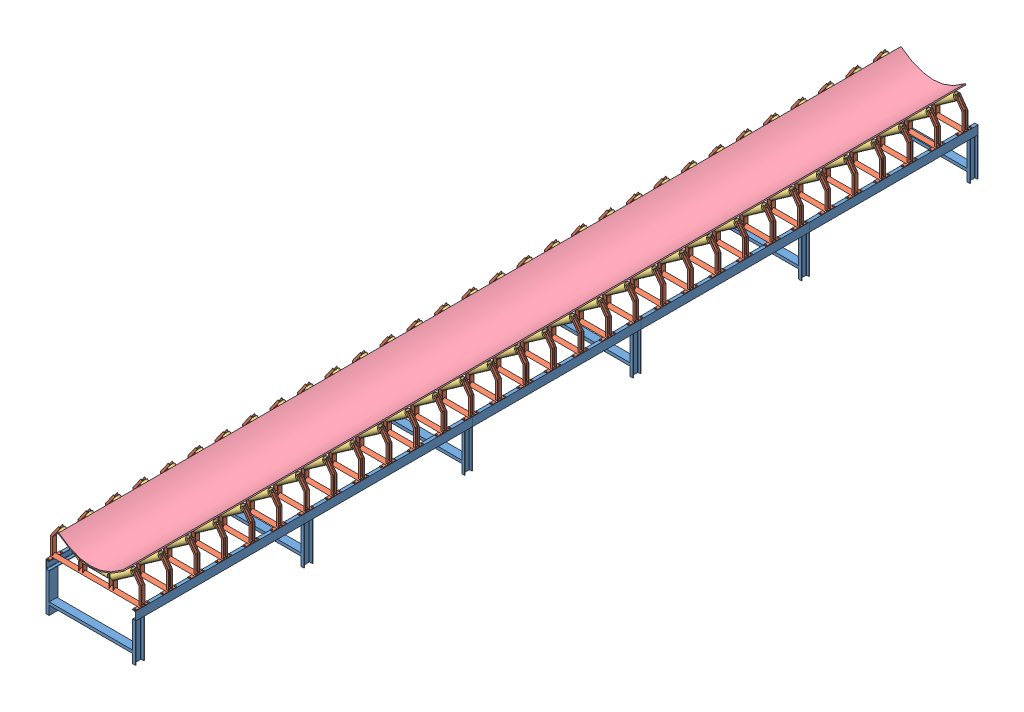
SolidWorks assembly Transportador, configuration Valor predeterminado. Lengths in mm.
Overall size (2310 1983.02 21500).
157 component instances, 4 part files, 8 mates.
Components (placement in the parent):
- Estrutura-1: Estrutura [Valor predeterminado<Como usinado>] at (49.1652 530.0341 0) size (2290 1200 21500)
- Desck3rolos-1: Desck3rolos [Valor predeterminado] at (242.5797 979.3864 -2491.6) size (2310 783.02 360)
  - Cavalete1800-1: Cavalete1800 [Valor predeterminado<Como usinado>] at (-193.4145 -362.4269 2311.6) size (2310 755.58 360)
  - RolodeCarga-1: RolodeCarga [Valor predeterminado] at (-860.2898 54.9269 2311.6) x (0.819152 -0.573576 0) z (-0.563806 -0.805199 0.183788) size (697 165 165)
  - RolodeCarga-2: RolodeCarga [Valor predeterminado] at (-193.4145 -134.9269 2311.6) x (-1 0 0) z (0 0.924225 0.381849) size (697 165 165)
  - RolodeCarga-3: RolodeCarga [Valor predeterminado] at (473.4609 54.9269 2311.6) x (0.819152 0.573576 0) z (0 0 1) size (697 165 165)
- Desck3rolos-2: Desck3rolos [Valor predeterminado] at (242.5797 979.3864 -3191.6) size (2310 783.02 360)
  - Cavalete1800-1: Cavalete1800 [Valor predeterminado<Como usinado>] at (-193.4145 -362.4269 2311.6) size (2310 755.58 360)
  - RolodeCarga-1: RolodeCarga [Valor predeterminado] at (-860.2898 54.9269 2311.6) x (0.819152 -0.573576 0) z (-0.563806 -0.805199 0.183788) size (697 165 165)
  - RolodeCarga-2: RolodeCarga [Valor predeterminado] at (-193.4145 -134.9269 2311.6) x (-1 0 0) z (0 0.924225 0.381849) size (697 165 165)
  - RolodeCarga-3: RolodeCarga [Valor predeterminado] at (473.4609 54.9269 2311.6) x (0.819152 0.573576 0) z (0 0 1) size (697 165 165)
- Desck3rolos-3: Desck3rolos [Valor predeterminado] at (242.5797 979.3864 -3891.6) size (2310 783.02 360)
  - Cavalete1800-1: Cavalete1800 [Valor predeterminado<Como usinado>] at (-193.4145 -362.4269 2311.6) size (2310 755.58 360)
  - RolodeCarga-1: RolodeCarga [Valor predeterminado] at (-860.2898 54.9269 2311.6) x (0.819152 -0.573576 0) z (-0.563806 -0.805199 0.183788) size (697 165 165)
  - RolodeCarga-2: RolodeCarga [Valor predeterminado] at (-193.4145 -134.9269 2311.6) x (-1 0 0) z (0 0.924225 0.381849) size (697 165 165)
  - RolodeCarga-3: RolodeCarga [Valor predeterminado] at (473.4609 54.9269 2311.6) x (0.819152 0.573576 0) z (0 0 1) size (697 165 165)
- Desck3rolos-4: Desck3rolos [Valor predeterminado] at (242.5797 979.3864 -4591.6) size (2310 783.02 360)
  - Cavalete1800-1: Cavalete1800 [Valor predeterminado<Como usinado>] at (-193.4145 -362.4269 2311.6) size (2310 755.58 360)
  - RolodeCarga-1: RolodeCarga [Valor predeterminado] at (-860.2898 54.9269 2311.6) x (0.819152 -0.573576 0) z (-0.563806 -0.805199 0.183788) size (697 165 165)
  - RolodeCarga-2: RolodeCarga [Valor predeterminado] at (-193.4145 -134.9269 2311.6) x (-1 0 0) z (0 0.924225 0.381849) size (697 165 165)
  - RolodeCarga-3: RolodeCarga [Valor predeterminado] at (473.4609 54.9269 2311.6) x (0.819152 0.573576 0) z (0 0 1) size (697 165 165)
- Desck3rolos-5: Desck3rolos [Valor predeterminado] at (242.5797 979.3864 -5291.6) size (2310 783.02 360)
  - Cavalete1800-1: Cavalete1800 [Valor predeterminado<Como usinado>] at (-193.4145 -362.4269 2311.6) size (2310 755.58 360)
  - RolodeCarga-1: RolodeCarga [Valor predeterminado] at (-860.2898 54.9269 2311.6) x (0.819152 -0.573576 0) z (-0.563806 -0.805199 0.183788) size (697 165 165)
  - RolodeCarga-2: RolodeCarga [Valor predeterminado] at (-193.4145 -134.9269 2311.6) x (-1 0 0) z (0 0.924225 0.381849) size (697 165 165)
  - RolodeCarga-3: RolodeCarga [Valor predeterminado] at (473.4609 54.9269 2311.6) x (0.819152 0.573576 0) z (0 0 1) size (697 165 165)
- Desck3rolos-6: Desck3rolos [Valor predeterminado] at (242.5797 979.3864 -5991.6) size (2310 783.02 360)
  - Cavalete1800-1: Cavalete1800 [Valor predeterminado<Como usinado>] at (-193.4145 -362.4269 2311.6) size (2310 755.58 360)
  - RolodeCarga-1: RolodeCarga [Valor predeterminado] at (-860.2898 54.9269 2311.6) x (0.819152 -0.573576 0) z (-0.563806 -0.805199 0.183788) size (697 165 165)
  - RolodeCarga-2: RolodeCarga [Valor predeterminado] at (-193.4145 -134.9269 2311.6) x (-1 0 0) z (0 0.924225 0.381849) size (697 165 165)
  - RolodeCarga-3: RolodeCarga [Valor predeterminado] at (473.4609 54.9269 2311.6) x (0.819152 0.573576 0) z (0 0 1) size (697 165 165)
- Desck3rolos-7: Desck3rolos [Valor predeterminado] at (242.5797 979.3864 -6691.6) size (2310 783.02 360)
  - Cavalete1800-1: Cavalete1800 [Valor predeterminado<Como usinado>] at (-193.4145 -362.4269 2311.6) size (2310 755.58 360)
  - RolodeCarga-1: RolodeCarga [Valor predeterminado] at (-860.2898 54.9269 2311.6) x (0.819152 -0.573576 0) z (-0.563806 -0.805199 0.183788) size (697 165 165)
  - RolodeCarga-2: RolodeCarga [Valor predeterminado] at (-193.4145 -134.9269 2311.6) x (-1 0 0) z (0 0.924225 0.381849) size (697 165 165)
  - RolodeCarga-3: RolodeCarga [Valor predeterminado] at (473.4609 54.9269 2311.6) x (0.819152 0.573576 0) z (0 0 1) size (697 165 165)
- Desck3rolos-8: Desck3rolos [Valor predeterminado] at (242.5797 979.3864 -7391.6) size (2310 783.02 360)
  - Cavalete1800-1: Cavalete1800 [Valor predeterminado<Como usinado>] at (-193.4145 -362.4269 2311.6) size (2310 755.58 360)
  - RolodeCarga-1: RolodeCarga [Valor predeterminado] at (-860.2898 54.9269 2311.6) x (0.819152 -0.573576 0) z (-0.563806 -0.805199 0.183788) size (697 165 165)
  - RolodeCarga-2: RolodeCarga [Valor predeterminado] at (-193.4145 -134.9269 2311.6) x (-1 0 0) z (0 0.924225 0.381849) size (697 165 165)
  - RolodeCarga-3: RolodeCarga [Valor predeterminado] at (473.4609 54.9269 2311.6) x (0.819152 0.573576 0) z (0 0 1) size (697 165 165)
- Desck3rolos-9: Desck3rolos [Valor predeterminado] at (242.5797 979.3864 -8091.6) size (2310 783.02 360)
  - Cavalete1800-1: Cavalete1800 [Valor predeterminado<Como usinado>] at (-193.4145 -362.4269 2311.6) size (2310 755.58 360)
  - RolodeCarga-1: RolodeCarga [Valor predeterminado] at (-860.2898 54.9269 2311.6) x (0.819152 -0.573576 0) z (-0.563806 -0.805199 0.183788) size (697 165 165)
  - RolodeCarga-2: RolodeCarga [Valor predeterminado] at (-193.4145 -134.9269 2311.6) x (-1 0 0) z (0 0.924225 0.381849) size (697 165 165)
  - RolodeCarga-3: RolodeCarga [Valor predeterminado] at (473.4609 54.9269 2311.6) x (0.819152 0.573576 0) z (0 0 1) size (697 165 165)
- Desck3rolos-10: Desck3rolos [Valor predeterminado] at (242.5797 979.3864 -8791.6) size (2310 783.02 360)
  - Cavalete1800-1: Cavalete1800 [Valor predeterminado<Como usinado>] at (-193.4145 -362.4269 2311.6) size (2310 755.58 360)
  - RolodeCarga-1: RolodeCarga [Valor predeterminado] at (-860.2898 54.9269 2311.6) x (0.819152 -0.573576 0) z (-0.563806 -0.805199 0.183788) size (697 165 165)
  - RolodeCarga-2: RolodeCarga [Valor predeterminado] at (-193.4145 -134.9269 2311.6) x (-1 0 0) z (0 0.924225 0.381849) size (697 165 165)
  - RolodeCarga-3: RolodeCarga [Valor predeterminado] at (473.4609 54.9269 2311.6) x (0.819152 0.573576 0) z (0 0 1) size (697 165 165)
- Desck3rolos-11: Desck3rolos [Valor predeterminado] at (242.5797 979.3864 -9491.6) size (2310 783.02 360)
  - Cavalete1800-1: Cavalete1800 [Valor predeterminado<Como usinado>] at (-193.4145 -362.4269 2311.6) size (2310 755.58 360)
  - RolodeCarga-1: RolodeCarga [Valor predeterminado] at (-860.2898 54.9269 2311.6) x (0.819152 -0.573576 0) z (-0.563806 -0.805199 0.183788) size (697 165 165)
  - RolodeCarga-2: RolodeCarga [Valor predeterminado] at (-193.4145 -134.9269 2311.6) x (-1 0 0) z (0 0.924225 0.381849) size (697 165 165)
  - RolodeCarga-3: RolodeCarga [Valor predeterminado] at (473.4609 54.9269 2311.6) x (0.819152 0.573576 0) z (0 0 1) size (697 165 165)
- Desck3rolos-12: Desck3rolos [Valor predeterminado] at (242.5797 979.3864 -10191.6) size (2310 783.02 360)
  - Cavalete1800-1: Cavalete1800 [Valor predeterminado<Como usinado>] at (-193.4145 -362.4269 2311.6) size (2310 755.58 360)
  - RolodeCarga-1: RolodeCarga [Valor predeterminado] at (-860.2898 54.9269 2311.6) x (0.819152 -0.573576 0) z (-0.563806 -0.805199 0.183788) size (697 165 165)
  - RolodeCarga-2: RolodeCarga [Valor predeterminado] at (-193.4145 -134.9269 2311.6) x (-1 0 0) z (0 0.924225 0.381849) size (697 165 165)
  - RolodeCarga-3: RolodeCarga [Valor predeterminado] at (473.4609 54.9269 2311.6) x (0.819152 0.573576 0) z (0 0 1) size (697 165 165)
- Desck3rolos-13: Desck3rolos [Valor predeterminado] at (242.5797 979.3864 -10891.6) size (2310 783.02 360)
  - Cavalete1800-1: Cavalete1800 [Valor predeterminado<Como usinado>] at (-193.4145 -362.4269 2311.6) size (2310 755.58 360)
  - RolodeCarga-1: RolodeCarga [Valor predeterminado] at (-860.2898 54.9269 2311.6) x (0.819152 -0.573576 0) z (-0.563806 -0.805199 0.183788) size (697 165 165)
  - RolodeCarga-2: RolodeCarga [Valor predeterminado] at (-193.4145 -134.9269 2311.6) x (-1 0 0) z (0 0.924225 0.381849) size (697 165 165)
  - RolodeCarga-3: RolodeCarga [Valor predeterminado] at (473.4609 54.9269 2311.6) x (0.819152 0.573576 0) z (0 0 1) size (697 165 165)
- Desck3rolos-14: Desck3rolos [Valor predeterminado] at (242.5797 979.3864 -11591.6) size (2310 783.02 360)
  - Cavalete1800-1: Cavalete1800 [Valor predeterminado<Como usinado>] at (-193.4145 -362.4269 2311.6) size (2310 755.58 360)
  - RolodeCarga-1: RolodeCarga [Valor predeterminado] at (-860.2898 54.9269 2311.6) x (0.819152 -0.573576 0) z (-0.563806 -0.805199 0.183788) size (697 165 165)
  - RolodeCarga-2: RolodeCarga [Valor predeterminado] at (-193.4145 -134.9269 2311.6) x (-1 0 0) z (0 0.924225 0.381849) size (697 165 165)
  - RolodeCarga-3: RolodeCarga [Valor predeterminado] at (473.4609 54.9269 2311.6) x (0.819152 0.573576 0) z (0 0 1) size (697 165 165)
- Desck3rolos-15: Desck3rolos [Valor predeterminado] at (242.5797 979.3864 -12291.6) size (2310 783.02 360)
  - Cavalete1800-1: Cavalete1800 [Valor predeterminado<Como usinado>] at (-193.4145 -362.4269 2311.6) size (2310 755.58 360)
  - RolodeCarga-1: RolodeCarga [Valor predeterminado] at (-860.2898 54.9269 2311.6) x (0.819152 -0.573576 0) z (-0.563806 -0.805199 0.183788) size (697 165 165)
  - RolodeCarga-2: RolodeCarga [Valor predeterminado] at (-193.4145 -134.9269 2311.6) x (-1 0 0) z (0 0.924225 0.381849) size (697 165 165)
  - RolodeCarga-3: RolodeCarga [Valor predeterminado] at (473.4609 54.9269 2311.6) x (0.819152 0.573576 0) z (0 0 1) size (697 165 165)
- Desck3rolos-16: Desck3rolos [Valor predeterminado] at (242.5797 979.3864 -12991.6) size (2310 783.02 360)
  - Cavalete1800-1: Cavalete1800 [Valor predeterminado<Como usinado>] at (-193.4145 -362.4269 2311.6) size (2310 755.58 360)
  - RolodeCarga-1: RolodeCarga [Valor predeterminado] at (-860.2898 54.9269 2311.6) x (0.819152 -0.573576 0) z (-0.563806 -0.805199 0.183788) size (697 165 165)
  - RolodeCarga-2: RolodeCarga [Valor predeterminado] at (-193.4145 -134.9269 2311.6) x (-1 0 0) z (0 0.924225 0.381849) size (697 165 165)
  - RolodeCarga-3: RolodeCarga [Valor predeterminado] at (473.4609 54.9269 2311.6) x (0.819152 0.573576 0) z (0 0 1) size (697 165 165)
- Desck3rolos-17: Desck3rolos [Valor predeterminado] at (242.5797 979.3864 -13691.6) size (2310 783.02 360)
  - Cavalete1800-1: Cavalete1800 [Valor predeterminado<Como usinado>] at (-193.4145 -362.4269 2311.6) size (2310 755.58 360)
  - RolodeCarga-1: RolodeCarga [Valor predeterminado] at (-860.2898 54.9269 2311.6) x (0.819152 -0.573576 0) z (-0.563806 -0.805199 0.183788) size (697 165 165)
  - RolodeCarga-2: RolodeCarga [Valor predeterminado] at (-193.4145 -134.9269 2311.6) x (-1 0 0) z (0 0.924225 0.381849) size (697 165 165)
  - RolodeCarga-3: RolodeCarga [Valor predeterminado] at (473.4609 54.9269 2311.6) x (0.819152 0.573576 0) z (0 0 1) size (697 165 165)
- Desck3rolos-18: Desck3rolos [Valor predeterminado] at (242.5797 979.3864 -14391.6) size (2310 783.02 360)
  - Cavalete1800-1: Cavalete1800 [Valor predeterminado<Como usinado>] at (-193.4145 -362.4269 2311.6) size (2310 755.58 360)
  - RolodeCarga-1: RolodeCarga [Valor predeterminado] at (-860.2898 54.9269 2311.6) x (0.819152 -0.573576 0) z (-0.563806 -0.805199 0.183788) size (697 165 165)
  - RolodeCarga-2: RolodeCarga [Valor predeterminado] at (-193.4145 -134.9269 2311.6) x (-1 0 0) z (0 0.924225 0.381849) size (697 165 165)
  - RolodeCarga-3: RolodeCarga [Valor predeterminado] at (473.4609 54.9269 2311.6) x (0.819152 0.573576 0) z (0 0 1) size (697 165 165)
- Desck3rolos-19: Desck3rolos [Valor predeterminado] at (242.5797 979.3864 -15091.6) size (2310 783.02 360)
  - Cavalete1800-1: Cavalete1800 [Valor predeterminado<Como usinado>] at (-193.4145 -362.4269 2311.6) size (2310 755.58 360)
  - RolodeCarga-1: RolodeCarga [Valor predeterminado] at (-860.2898 54.9269 2311.6) x (0.819152 -0.573576 0) z (-0.563806 -0.805199 0.183788) size (697 165 165)
  - RolodeCarga-2: RolodeCarga [Valor predeterminado] at (-193.4145 -134.9269 2311.6) x (-1 0 0) z (0 0.924225 0.381849) size (697 165 165)
  - RolodeCarga-3: RolodeCarga [Valor predeterminado] at (473.4609 54.9269 2311.6) x (0.819152 0.573576 0) z (0 0 1) size (697 165 165)
- Desck3rolos-20: Desck3rolos [Valor predeterminado] at (242.5797 979.3864 -15791.6) size (2310 783.02 360)
  - Cavalete1800-1: Cavalete1800 [Valor predeterminado<Como usinado>] at (-193.4145 -362.4269 2311.6) size (2310 755.58 360)
  - RolodeCarga-1: RolodeCarga [Valor predeterminado] at (-860.2898 54.9269 2311.6) x (0.819152 -0.573576 0) z (-0.563806 -0.805199 0.183788) size (697 165 165)
  - RolodeCarga-2: RolodeCarga [Valor predeterminado] at (-193.4145 -134.9269 2311.6) x (-1 0 0) z (0 0.924225 0.381849) size (697 165 165)
  - RolodeCarga-3: RolodeCarga [Valor predeterminado] at (473.4609 54.9269 2311.6) x (0.819152 0.573576 0) z (0 0 1) size (697 165 165)
- Desck3rolos-21: Desck3rolos [Valor predeterminado] at (242.5797 979.3864 -16491.6) size (2310 783.02 360)
  - Cavalete1800-1: Cavalete1800 [Valor predeterminado<Como usinado>] at (-193.4145 -362.4269 2311.6) size (2310 755.58 360)
  - RolodeCarga-1: RolodeCarga [Valor predeterminado] at (-860.2898 54.9269 2311.6) x (0.819152 -0.573576 0) z (-0.563806 -0.805199 0.183788) size (697 165 165)
  - RolodeCarga-2: RolodeCarga [Valor predeterminado] at (-193.4145 -134.9269 2311.6) x (-1 0 0) z (0 0.924225 0.381849) size (697 165 165)
  - RolodeCarga-3: RolodeCarga [Valor predeterminado] at (473.4609 54.9269 2311.6) x (0.819152 0.573576 0) z (0 0 1) size (697 165 165)
- Desck3rolos-22: Desck3rolos [Valor predeterminado] at (242.5797 979.3864 -17191.6) size (2310 783.02 360)
  - Cavalete1800-1: Cavalete1800 [Valor predeterminado<Como usinado>] at (-193.4145 -362.4269 2311.6) size (2310 755.58 360)
  - RolodeCarga-1: RolodeCarga [Valor predeterminado] at (-860.2898 54.9269 2311.6) x (0.819152 -0.573576 0) z (-0.563806 -0.805199 0.183788) size (697 165 165)
  - RolodeCarga-2: RolodeCarga [Valor predeterminado] at (-193.4145 -134.9269 2311.6) x (-1 0 0) z (0 0.924225 0.381849) size (697 165 165)
  - RolodeCarga-3: RolodeCarga [Valor predeterminado] at (473.4609 54.9269 2311.6) x (0.819152 0.573576 0) z (0 0 1) size (697 165 165)
- Desck3rolos-23: Desck3rolos [Valor predeterminado] at (242.5797 979.3864 -17891.6) size (2310 783.02 360)
  - Cavalete1800-1: Cavalete1800 [Valor predeterminado<Como usinado>] at (-193.4145 -362.4269 2311.6) size (2310 755.58 360)
  - RolodeCarga-1: RolodeCarga [Valor predeterminado] at (-860.2898 54.9269 2311.6) x (0.819152 -0.573576 0) z (-0.563806 -0.805199 0.183788) size (697 165 165)
  - RolodeCarga-2: RolodeCarga [Valor predeterminado] at (-193.4145 -134.9269 2311.6) x (-1 0 0) z (0 0.924225 0.381849) size (697 165 165)
  - RolodeCarga-3: RolodeCarga [Valor predeterminado] at (473.4609 54.9269 2311.6) x (0.819152 0.573576 0) z (0 0 1) size (697 165 165)
- Desck3rolos-24: Desck3rolos [Valor predeterminado] at (242.5797 979.3864 -18591.6) size (2310 783.02 360)
  - Cavalete1800-1: Cavalete1800 [Valor predeterminado<Como usinado>] at (-193.4145 -362.4269 2311.6) size (2310 755.58 360)
  - RolodeCarga-1: RolodeCarga [Valor predeterminado] at (-860.2898 54.9269 2311.6) x (0.819152 -0.573576 0) z (-0.563806 -0.805199 0.183788) size (697 165 165)
  - RolodeCarga-2: RolodeCarga [Valor predeterminado] at (-193.4145 -134.9269 2311.6) x (-1 0 0) z (0 0.924225 0.381849) size (697 165 165)
  - RolodeCarga-3: RolodeCarga [Valor predeterminado] at (473.4609 54.9269 2311.6) x (0.819152 0.573576 0) z (0 0 1) size (697 165 165)
- Desck3rolos-25: Desck3rolos [Valor predeterminado] at (242.5797 979.3864 -19291.6) size (2310 783.02 360)
  - Cavalete1800-1: Cavalete1800 [Valor predeterminado<Como usinado>] at (-193.4145 -362.4269 2311.6) size (2310 755.58 360)
  - RolodeCarga-1: RolodeCarga [Valor predeterminado] at (-860.2898 54.9269 2311.6) x (0.819152 -0.573576 0) z (-0.563806 -0.805199 0.183788) size (697 165 165)
  - RolodeCarga-2: RolodeCarga [Valor predeterminado] at (-193.4145 -134.9269 2311.6) x (-1 0 0) z (0 0.924225 0.381849) size (697 165 165)
  - RolodeCarga-3: RolodeCarga [Valor predeterminado] at (473.4609 54.9269 2311.6) x (0.819152 0.573576 0) z (0 0 1) size (697 165 165)
- Desck3rolos-26: Desck3rolos [Valor predeterminado] at (242.5797 979.3864 -19991.6) size (2310 783.02 360)
  - Cavalete1800-1: Cavalete1800 [Valor predeterminado<Como usinado>] at (-193.4145 -362.4269 2311.6) size (2310 755.58 360)
  - RolodeCarga-1: RolodeCarga [Valor predeterminado] at (-860.2898 54.9269 2311.6) x (0.819152 -0.573576 0) z (-0.563806 -0.805199 0.183788) size (697 165 165)
  - RolodeCarga-2: RolodeCarga [Valor predeterminado] at (-193.4145 -134.9269 2311.6) x (-1 0 0) z (0 0.924225 0.381849) size (697 165 165)
  - RolodeCarga-3: RolodeCarga [Valor predeterminado] at (473.4609 54.9269 2311.6) x (0.819152 0.573576 0) z (0 0 1) size (697 165 165)
- Desck3rolos-27: Desck3rolos [Valor predeterminado] at (242.5797 979.3864 -20691.6) size (2310 783.02 360)
  - Cavalete1800-1: Cavalete1800 [Valor predeterminado<Como usinado>] at (-193.4145 -362.4269 2311.6) size (2310 755.58 360)
  - RolodeCarga-1: RolodeCarga [Valor predeterminado] at (-860.2898 54.9269 2311.6) x (0.819152 -0.573576 0) z (-0.563806 -0.805199 0.183788) size (697 165 165)
  - RolodeCarga-2: RolodeCarga [Valor predeterminado] at (-193.4145 -134.9269 2311.6) x (-1 0 0) z (0 0.924225 0.381849) size (697 165 165)
  - RolodeCarga-3: RolodeCarga [Valor predeterminado] at (473.4609 54.9269 2311.6) x (0.819152 0.573576 0) z (0 0 1) size (697 165 165)
- Desck3rolos-28: Desck3rolos [Valor predeterminado] at (242.5797 979.3864 -21391.6) size (2310 783.02 360)
  - Cavalete1800-1: Cavalete1800 [Valor predeterminado<Como usinado>] at (-193.4145 -362.4269 2311.6) size (2310 755.58 360)
  - RolodeCarga-1: RolodeCarga [Valor predeterminado] at (-860.2898 54.9269 2311.6) x (0.819152 -0.573576 0) z (-0.563806 -0.805199 0.183788) size (697 165 165)
  - RolodeCarga-2: RolodeCarga [Valor predeterminado] at (-193.4145 -134.9269 2311.6) x (-1 0 0) z (0 0.924225 0.381849) size (697 165 165)
  - RolodeCarga-3: RolodeCarga [Valor predeterminado] at (473.4609 54.9269 2311.6) x (0.819152 0.573576 0) z (0 0 1) size (697 165 165)
- Desck3rolos-29: Desck3rolos [Valor predeterminado] at (242.5797 979.3864 -22091.6) size (2310 783.02 360)
  - Cavalete1800-1: Cavalete1800 [Valor predeterminado<Como usinado>] at (-193.4145 -362.4269 2311.6) size (2310 755.58 360)
  - RolodeCarga-1: RolodeCarga [Valor predeterminado] at (-860.2898 54.9269 2311.6) x (0.819152 -0.573576 0) z (-0.563806 -0.805199 0.183788) size (697 165 165)
  - RolodeCarga-2: RolodeCarga [Valor predeterminado] at (-193.4145 -134.9269 2311.6) x (-1 0 0) z (0 0.924225 0.381849) size (697 165 165)
  - RolodeCarga-3: RolodeCarga [Valor predeterminado] at (473.4609 54.9269 2311.6) x (0.819152 0.573576 0) z (0 0 1) size (697 165 165)
- Desck3rolos-30: Desck3rolos [Valor predeterminado] at (242.5797 979.3864 -22791.6) size (2310 783.02 360)
  - Cavalete1800-1: Cavalete1800 [Valor predeterminado<Como usinado>] at (-193.4145 -362.4269 2311.6) size (2310 755.58 360)
  - RolodeCarga-1: RolodeCarga [Valor predeterminado] at (-860.2898 54.9269 2311.6) x (0.819152 -0.573576 0) z (-0.563806 -0.805199 0.183788) size (697 165 165)
  - RolodeCarga-2: RolodeCarga [Valor predeterminado] at (-193.4145 -134.9269 2311.6) x (-1 0 0) z (0 0.924225 0.381849) size (697 165 165)
  - RolodeCarga-3: RolodeCarga [Valor predeterminado] at (473.4609 54.9269 2311.6) x (0.819152 0.573576 0) z (0 0 1) size (697 165 165)
- Desck3rolos-31: Desck3rolos [Valor predeterminado] at (242.5797 979.3864 -23491.6) size (2310 783.02 360)
  - Cavalete1800-1: Cavalete1800 [Valor predeterminado<Como usinado>] at (-193.4145 -362.4269 2311.6) size (2310 755.58 360)
  - RolodeCarga-1: RolodeCarga [Valor predeterminado] at (-860.2898 54.9269 2311.6) x (0.819152 -0.573576 0) z (-0.563806 -0.805199 0.183788) size (697 165 165)
  - RolodeCarga-2: RolodeCarga [Valor predeterminado] at (-193.4145 -134.9269 2311.6) x (-1 0 0) z (0 0.924225 0.381849) size (697 165 165)
  - RolodeCarga-3: RolodeCarga [Valor predeterminado] at (473.4609 54.9269 2311.6) x (0.819152 0.573576 0) z (0 0 1) size (697 165 165)
- Correia-1: Correia [Valor predeterminado] at origin size (1673.46 352.65 21500)
Mates (geometry in assembly coordinates):
- Coincidente1: coincident anti-aligned: plane of Desck3rolos-1/Cavalete1800-1 through (-1093.9348 530.0341 -360) normal (0 -1 0); plane of Estrutura-1 through (-1015.8348 530.0341 0) normal (0 1 0)
- Coincidente3: coincident anti-aligned: line of Desck3rolos-1/Cavalete1800-1 through (-1055.8348 530.0341 -41) axis (0 0 -1); line of Estrutura-1 through (-1055.8348 530.0341 -4300) axis (0 0 1)
- Coincidente4: coincident aligned: plane of Estrutura-1 through (-1015.8348 530.0341 0) normal (0 0 1); plane of Desck3rolos-1/Cavalete1800-1 through (-2198.9348 468.5087 0) normal (0 0 1)
- Coincidente5: coincident aligned: plane of Estrutura-1 through (49.1652 530.0341 0) normal (0 0 1); plane of assembly through (0 0 0) normal (0 0 1)
- No local3: in place: plane of Correia-1 through (0 0 0) normal (0 0 1); moOrthogonalPlaneRef_w of Correia-1 through (0 0 0) normal (0 1 0); plane of Correia-1 through (0 0 0) normal (1 0 0); unknown of Correia-1
- Coincidente12: coincident aligned: plane of Correia-1; plane of assembly
- Coincidente13: coincident aligned: plane of Correia-1 through (0 0 0) normal (0 1 0); moOrthogonalPlaneRef_w of assembly
- Coincidente14: coincident anti-aligned: plane of Correia-1 through (0 0 0) normal (1 0 0); moOrthogonalPlaneRef_w of assembly
